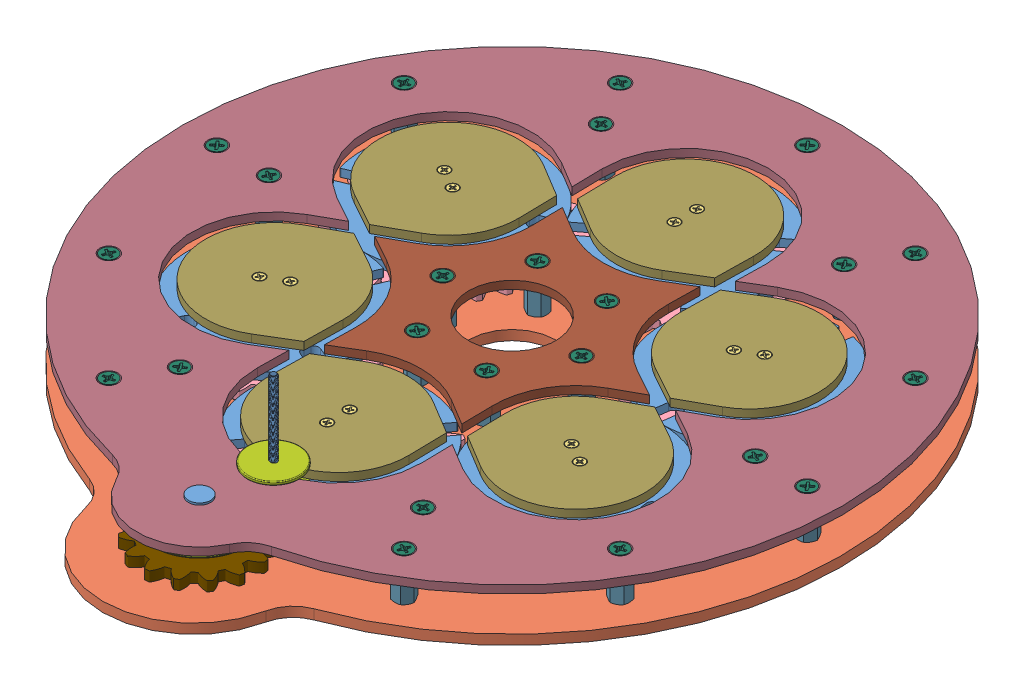
SolidWorks assembly braider_assembly, configuration Default. Lengths in mm.
Overall size (407.81 79.95 544.26).
176 component instances, 26 part files, 54 mates.
Components (placement in the parent):
- Assem3-1: Assem3 [Default] at (8.7677 19.1661 -76.7438) x (-0.794369 0 0.607435) z (-0.607435 0 -0.794369) size (188.23 25.6 124.49)
  - transfer_plate-4: transfer_plate [Default] at (0 -4.5661 0) size (188.23 4.5 124.49)
  - handoff_shaft-1: handoff_shaft [Default] at (0 -4.5661 0) x (-0.685538 0 0.728037) z (-0.728037 0 -0.685538) size (25.4 25.6 25.4)
  - transfer_spacer-1: transfer_spacer [Default] at (0 -9.0661 0) x (0 0 -1) z (0 1 0) size (40 40 4.5)
  - 25 tooth large gear2-2: 25 tooth large gear2 [Default] at (0 -13.5661 0) size (105.94 4.5 105.74)
  - 91771A169-1: 91771A169 [91771A169] at (0 -2.1743 16.8627) x (1 0 0) z (0 1 0) size (6.65 6.65 15.37)
  - 91771A169-2: 91771A169 [91771A169] at (0 -2.1743 -16.8627) x (1 0 0) z (0 1 0) size (6.65 6.65 15.37)
- Assem3-2: Assem3 [Default] at (-77.8348 19.1661 -26.7438) x (0.923102 0 -0.384556) z (0.384556 0 0.923102) size (188.23 25.6 124.49)
  - transfer_plate-4: transfer_plate [Default] at (0 -4.5661 0) size (188.23 4.5 124.49)
  - handoff_shaft-1: handoff_shaft [Default] at (0 -4.5661 0) x (-0.685538 0 0.728037) z (-0.728037 0 -0.685538) size (25.4 25.6 25.4)
  - transfer_spacer-1: transfer_spacer [Default] at (0 -9.0661 0) x (0 0 -1) z (0 1 0) size (40 40 4.5)
  - 25 tooth large gear2-2: 25 tooth large gear2 [Default] at (0 -13.5661 0) size (105.94 4.5 105.74)
  - 91771A169-1: 91771A169 [91771A169] at (0 -2.1743 16.8627) x (1 0 0) z (0 1 0) size (6.65 6.65 15.37)
  - 91771A169-2: 91771A169 [91771A169] at (0 -2.1743 -16.8627) x (1 0 0) z (0 1 0) size (6.65 6.65 15.37)
- Assem3-3: Assem3 [Default] at (-77.8348 19.1661 73.2562) x (0.922465 0 0.386081) z (-0.386081 0 0.922465) size (188.23 25.6 124.49)
  - transfer_plate-4: transfer_plate [Default] at (0 -4.5661 0) size (188.23 4.5 124.49)
  - handoff_shaft-1: handoff_shaft [Default] at (0 -4.5661 0) x (-0.685538 0 0.728037) z (-0.728037 0 -0.685538) size (25.4 25.6 25.4)
  - transfer_spacer-1: transfer_spacer [Default] at (0 -9.0661 0) x (0 0 -1) z (0 1 0) size (40 40 4.5)
  - 25 tooth large gear2-2: 25 tooth large gear2 [Default] at (0 -13.5661 0) size (105.94 4.5 105.74)
  - 91771A169-1: 91771A169 [91771A169] at (0 -2.1743 16.8627) x (1 0 0) z (0 1 0) size (6.65 6.65 15.37)
  - 91771A169-2: 91771A169 [91771A169] at (0 -2.1743 -16.8627) x (1 0 0) z (0 1 0) size (6.65 6.65 15.37)
- Assem3-4: Assem3 [Default] at (8.7677 19.1661 123.2562) x (-0.795809 0 -0.605547) z (0.605547 0 -0.795809) size (188.23 25.6 124.49)
  - transfer_plate-4: transfer_plate [Default] at (0 -4.5661 0) size (188.23 4.5 124.49)
  - handoff_shaft-1: handoff_shaft [Default] at (0 -4.5661 0) x (-0.685538 0 0.728037) z (-0.728037 0 -0.685538) size (25.4 25.6 25.4)
  - transfer_spacer-1: transfer_spacer [Default] at (0 -9.0661 0) x (0 0 -1) z (0 1 0) size (40 40 4.5)
  - 25 tooth large gear2-2: 25 tooth large gear2 [Default] at (0 -13.5661 0) size (105.94 4.5 105.74)
  - 91771A169-1: 91771A169 [91771A169] at (0 -2.1743 16.8627) x (1 0 0) z (0 1 0) size (6.65 6.65 15.37)
  - 91771A169-2: 91771A169 [91771A169] at (0 -2.1743 -16.8627) x (1 0 0) z (0 1 0) size (6.65 6.65 15.37)
- Assem3-5: Assem3 [Default] at (95.3702 19.1661 73.2562) x (-0.130269 0 -0.991479) z (0.991479 0 -0.130269) size (188.23 25.6 124.49)
  - transfer_plate-4: transfer_plate [Default] at (0 -4.5661 0) size (188.23 4.5 124.49)
  - handoff_shaft-1: handoff_shaft [Default] at (0 -4.5661 0) x (-0.685538 0 0.728037) z (-0.728037 0 -0.685538) size (25.4 25.6 25.4)
  - transfer_spacer-1: transfer_spacer [Default] at (0 -9.0661 0) x (0 0 -1) z (0 1 0) size (40 40 4.5)
  - 25 tooth large gear2-2: 25 tooth large gear2 [Default] at (0 -13.5661 0) size (105.94 4.5 105.74)
  - 91771A169-1: 91771A169 [91771A169] at (0 -2.1743 16.8627) x (1 0 0) z (0 1 0) size (6.65 6.65 15.37)
  - 91771A169-2: 91771A169 [91771A169] at (0 -2.1743 -16.8627) x (1 0 0) z (0 1 0) size (6.65 6.65 15.37)
- Assem3-6: Assem3 [Default] at (95.3702 19.1661 -26.7438) x (-0.130469 0 0.991452) z (-0.991452 0 -0.130469) size (188.23 25.6 124.49)
  - transfer_plate-4: transfer_plate [Default] at (0 -4.5661 0) size (188.23 4.5 124.49)
  - handoff_shaft-1: handoff_shaft [Default] at (0 -4.5661 0) x (-0.685538 0 0.728037) z (-0.728037 0 -0.685538) size (25.4 25.6 25.4)
  - transfer_spacer-1: transfer_spacer [Default] at (0 -9.0661 0) x (0 0 -1) z (0 1 0) size (40 40 4.5)
  - 25 tooth large gear2-2: 25 tooth large gear2 [Default] at (0 -13.5661 0) size (105.94 4.5 105.74)
  - 91771A169-1: 91771A169 [91771A169] at (0 -2.1743 16.8627) x (1 0 0) z (0 1 0) size (6.65 6.65 15.37)
  - 91771A169-2: 91771A169 [91771A169] at (0 -2.1743 -16.8627) x (1 0 0) z (0 1 0) size (6.65 6.65 15.37)
- Part11-1: Part11 [Default] x (1 0 0) z (0 1 0) size (200 378.38 5.6)
- Part15-1: Part15 [Default] at (-86.6025 0 -50) x (-0.916904 0 0.399107) z (0 1 0)
- spindle_sub_assembly-5: spindle_sub_assembly [Default] at (38.2222 14.0833 186.1922) x (0.387319 0 -0.921946) z (-0.921946 0 -0.387319) size (37.67 65.55 37.67)
  - spindle_shaft-1: spindle_shaft [Default] at (9.1523 -6.9167 29.8135) size (8 5.6 8)
  - top_ring-1: top_ring [Default] at (4.3402 31.9804 168.7359) x (0.991452 0.000169 -0.130469) z (0.000177 -1 0.000051) size (30 30 2.01)
  - top_ring-2: top_ring [Default] at (-10.4741 23.8804 -107.7998) x (-0.953205 0.000169 0.302326) z (-0.000183 -1 -0.000019) size (30 30 2.01)
  - oval_slider-1: oval_slider [Default] at (9.1523 -10.4167 29.8135) x (0.496424 0 -0.86808) z (-0.86808 0 -0.496424) size (21.5 5.6 6.52)
  - 4_8_shim-4: 4_8_shim [Default] at (9.1523 -10.4167 29.8135) size (8 0.5 8)
  - 4_8_shim-5: 4_8_shim [Default] at (9.1523 -7.9167 29.8135) size (8 0.5 8)
  - 4_8_shim-6: 4_8_shim [Default] at (9.1523 -7.4167 29.8135) size (8 0.5 8)
  - m4_60mm-1: m4_60mm [92000A248] at (9.1523 -61.3167 29.8135) x (1 0 0) z (0 1 0) size (8 8 65.55)
- top_slide_plate_sub_assembly-1: top_slide_plate_sub_assembly [Default] at (8.7677 30.1 23.2562) x (-1 0 0) z (0 0 -1) size (407.81 4.5 419.9)
  - top_slide_plate_inner_ring-1: top_slide_plate_inner_ring [Default] at (0 -67.0456 0) x (-1 0 0) z (0 1 0) size (198.46 137.03 4.5)
  - top_slide_plate_segment-1: top_slide_plate_segment [Default] at (-1.731 0 -94.8037) x (1 0 0) z (0 0 -1) size (111.69 4.5 164.88)
  - top_slide_plate_segment-13: top_slide_plate_segment [Default] at (81.2369 0 -48.9009) x (0.5 0 0.866025) z (0.866025 0 -0.5) size (111.69 4.5 164.88)
  - top_slide_plate_segment-14: top_slide_plate_segment [Default] at (82.9679 0 45.9028) x (-0.5 0 0.866025) z (0.866025 0 0.5) size (111.69 4.5 164.88)
  - top_slide_plate_segment-15: top_slide_plate_segment [Default] at (1.731 0 94.8037) x (-1 0 0) z (0 0 1) size (111.69 4.5 164.88)
  - top_slide_plate_segment-16: top_slide_plate_segment [Default] at (-81.2369 0 48.9009) x (-0.5 0 -0.866025) z (-0.866025 0 0.5) size (111.69 4.5 164.88)
  - top_slide_plate_segment-17: top_slide_plate_segment [Default] at (-82.9679 0 -45.9028) x (0.5 0 -0.866025) z (-0.866025 0 -0.5) size (111.69 4.5 164.88)
  - top_slide_plate_outer_ring-2: top_slide_plate_outer_ring [Default] at origin size (407.81 4.5 419.9)
- standoff-7: standoff [95947A731] at (-76.2323 15.6 170.4805) x (-0.868924 0 0.494945) z (0 -1 0) size (10 11.55 21.1)
- m5 14mm-1: m5 14mm [91420A324] at (-61.2323 27.6 144.4998) x (0.552479 0 0.833527) z (0 1 0) size (9.2 9.2 14.67)
- m5 14mm-13: m5 14mm [91420A324] at (-76.2323 27.6 170.4805) x (-0.986594 0 0.163192) z (0 1 0) size (9.2 9.2 14.67)
- m5 14mm-19: m5 14mm [91420A324] at (-11.2323 27.6 -11.3848) x (-0.401704 0 -0.915769) z (0 1 0) size (9.2 9.2 14.67)
- slider_bearing_assembly-1: slider_bearing_assembly [Default] at (-0.8143 7.35 212.7934) x (1 0 0) z (0 -1 0) size (10 10 3.75)
  - 6-32_thead__175_thick-1-1: 6-32_thead__175_thick-1 [Default] at (-3.85 0 -1.125) size (1.08 1.08 1.75)
    - 6-32_thead__125_thick-1-1: 6-32_thead__125_thick-1 [Default] at (0 0 0.2386) size (1.08 1.08 1.27)
    - 6-32_thead__175_thick-1-1: 6-32_thead__175_thick-1 [Default] at origin size (1.08 1.08 0.48)
  - 6-32_thead__175_thick-1-2: 6-32_thead__175_thick-1 [Default] at (-2.7224 2.7224 -1.125) x (0.707107 -0.707107 0) z (0 0 1) size (1.08 1.08 1.75)
    - 6-32_thead__125_thick-1-1: 6-32_thead__125_thick-1 [Default] at (0 0 0.2386) size (1.08 1.08 1.27)
    - 6-32_thead__175_thick-1-1: 6-32_thead__175_thick-1 [Default] at origin size (1.08 1.08 0.48)
  - 6-32_thead__175_thick-1-3: 6-32_thead__175_thick-1 [Default] at (0 3.85 -1.125) x (0 -1 0) z (0 0 1) size (1.08 1.08 1.75)
    - 6-32_thead__125_thick-1-1: 6-32_thead__125_thick-1 [Default] at (0 0 0.2386) size (1.08 1.08 1.27)
    - 6-32_thead__175_thick-1-1: 6-32_thead__175_thick-1 [Default] at origin size (1.08 1.08 0.48)
  - 6-32_thead__175_thick-1-4: 6-32_thead__175_thick-1 [Default] at (2.7224 2.7224 -1.125) x (-0.707107 -0.707107 0) z (0 0 1) size (1.08 1.08 1.75)
    - 6-32_thead__125_thick-1-1: 6-32_thead__125_thick-1 [Default] at (0 0 0.2386) size (1.08 1.08 1.27)
    - 6-32_thead__175_thick-1-1: 6-32_thead__175_thick-1 [Default] at origin size (1.08 1.08 0.48)
  - 6-32_thead__175_thick-1-5: 6-32_thead__175_thick-1 [Default] at (3.85 0 -1.125) x (-1 0 0) z (0 0 1) size (1.08 1.08 1.75)
    - 6-32_thead__125_thick-1-1: 6-32_thead__125_thick-1 [Default] at (0 0 0.2386) size (1.08 1.08 1.27)
    - 6-32_thead__175_thick-1-1: 6-32_thead__175_thick-1 [Default] at origin size (1.08 1.08 0.48)
  - 6-32_thead__175_thick-1-6: 6-32_thead__175_thick-1 [Default] at (2.7224 -2.7224 -1.125) x (-0.707107 0.707107 0) z (0 0 1) size (1.08 1.08 1.75)
    - 6-32_thead__125_thick-1-1: 6-32_thead__125_thick-1 [Default] at (0 0 0.2386) size (1.08 1.08 1.27)
    - 6-32_thead__175_thick-1-1: 6-32_thead__175_thick-1 [Default] at origin size (1.08 1.08 0.48)
  - 6-32_thead__175_thick-1-7: 6-32_thead__175_thick-1 [Default] at (0 -3.85 -1.125) x (0 1 0) z (0 0 1) size (1.08 1.08 1.75)
    - 6-32_thead__125_thick-1-1: 6-32_thead__125_thick-1 [Default] at (0 0 0.2386) size (1.08 1.08 1.27)
    - 6-32_thead__175_thick-1-1: 6-32_thead__175_thick-1 [Default] at origin size (1.08 1.08 0.48)
  - 6-32_thead__175_thick-1-8: 6-32_thead__175_thick-1 [Default] at (-2.7224 -2.7224 -1.125) x (0.707107 0.707107 0) z (0 0 1) size (1.08 1.08 1.75)
    - 6-32_thead__125_thick-1-1: 6-32_thead__125_thick-1 [Default] at (0 0 0.2386) size (1.08 1.08 1.27)
    - 6-32_thead__175_thick-1-1: 6-32_thead__175_thick-1 [Default] at origin size (1.08 1.08 0.48)
  - 6-32_thead__175_thick-1-9: 6-32_thead__175_thick-1 [Default] at (0 3.85 0.875) x (0.707107 -0.707107 0) z (0 0 1) size (1.08 1.08 1.75)
    - 6-32_thead__125_thick-1-1: 6-32_thead__125_thick-1 [Default] at (0 0 0.2386) size (1.08 1.08 1.27)
    - 6-32_thead__175_thick-1-1: 6-32_thead__175_thick-1 [Default] at origin size (1.08 1.08 0.48)
  - 6-32_thead__175_thick-1-10: 6-32_thead__175_thick-1 [Default] at (-2.7224 2.7224 0.875) size (1.08 1.08 1.75)
    - 6-32_thead__125_thick-1-1: 6-32_thead__125_thick-1 [Default] at (0 0 0.2386) size (1.08 1.08 1.27)
    - 6-32_thead__175_thick-1-1: 6-32_thead__175_thick-1 [Default] at origin size (1.08 1.08 0.48)
  - 6-32_thead__175_thick-1-11: 6-32_thead__175_thick-1 [Default] at (-3.85 0 0.875) x (0.707107 0.707107 0) z (0 0 1) size (1.08 1.08 1.75)
    - 6-32_thead__125_thick-1-1: 6-32_thead__125_thick-1 [Default] at (0 0 0.2386) size (1.08 1.08 1.27)
    - 6-32_thead__175_thick-1-1: 6-32_thead__175_thick-1 [Default] at origin size (1.08 1.08 0.48)
  - 6-32_thead__175_thick-1-12: 6-32_thead__175_thick-1 [Default] at (-2.7224 -2.7224 0.875) x (0 1 0) z (0 0 1) size (1.08 1.08 1.75)
    - 6-32_thead__125_thick-1-1: 6-32_thead__125_thick-1 [Default] at (0 0 0.2386) size (1.08 1.08 1.27)
    - 6-32_thead__175_thick-1-1: 6-32_thead__175_thick-1 [Default] at origin size (1.08 1.08 0.48)
  - 6-32_thead__175_thick-1-13: 6-32_thead__175_thick-1 [Default] at (0 -3.85 0.875) x (-0.707107 0.707107 0) z (0 0 1) size (1.08 1.08 1.75)
    - 6-32_thead__125_thick-1-1: 6-32_thead__125_thick-1 [Default] at (0 0 0.2386) size (1.08 1.08 1.27)
    - 6-32_thead__175_thick-1-1: 6-32_thead__175_thick-1 [Default] at origin size (1.08 1.08 0.48)
  - 6-32_thead__175_thick-1-14: 6-32_thead__175_thick-1 [Default] at (2.7224 -2.7224 0.875) x (-1 0 0) z (0 0 1) size (1.08 1.08 1.75)
    - 6-32_thead__125_thick-1-1: 6-32_thead__125_thick-1 [Default] at (0 0 0.2386) size (1.08 1.08 1.27)
    - 6-32_thead__175_thick-1-1: 6-32_thead__175_thick-1 [Default] at origin size (1.08 1.08 0.48)
  - 6-32_thead__175_thick-1-15: 6-32_thead__175_thick-1 [Default] at (3.85 0 0.875) x (-0.707107 -0.707107 0) z (0 0 1) size (1.08 1.08 1.75)
    - 6-32_thead__125_thick-1-1: 6-32_thead__125_thick-1 [Default] at (0 0 0.2386) size (1.08 1.08 1.27)
    - 6-32_thead__175_thick-1-1: 6-32_thead__175_thick-1 [Default] at origin size (1.08 1.08 0.48)
  - 6-32_thead__175_thick-1-16: 6-32_thead__175_thick-1 [Default] at (2.7224 2.7224 0.875) x (0 -1 0) z (0 0 1) size (1.08 1.08 1.75)
    - 6-32_thead__125_thick-1-1: 6-32_thead__125_thick-1 [Default] at (0 0 0.2386) size (1.08 1.08 1.27)
    - 6-32_thead__175_thick-1-1: 6-32_thead__175_thick-1 [Default] at origin size (1.08 1.08 0.48)
  - 545364-1-1: 545364-1 [Default] at origin size (10 10 3.75)
- standoff-35: standoff [95947A731] at (-11.2323 15.6 -11.3848) x (1 0 0) z (0 -1 0) size (10 11.55 21.1)
- standoff-41: standoff [95947A731] at (-61.2323 15.6 144.4998) x (1 0 0) z (0 -1 0) size (10 11.55 21.1)
- 2 inch pulley-2: 2 inch pulley [Default] at (8.7774 21.233 203.2562) x (-0.976231 0 -0.216734) z (0 -1 0) size (53.81 53.81 6.1)
- half inch bore hub mount-2: half inch bore hub mount [Default] at (8.7774 8.66 203.2562) x (-0.976231 0 -0.216734) z (0.216734 0 -0.976231) size (20.57 6.99 20.57)
- 15 tooth small gear-4: 15 tooth small gear [Default] at (8.7774 5.6 203.2562) x (-0.999686 0 -0.025054) z (0.025054 0 -0.999686) size (65.52 5.6 65.88)
- half inch shaft-1: half inch shaft [Default] at (8.7774 18.9636 203.2562) x (-0.9981 0 -0.061613) z (0.061613 0 -0.9981) size (12.7 31.2 12.7)
- Part13-2: Part13 [Default] at (8.7677 5.6 23.2562) x (-1 0 0) z (0 0 -1) size (380 5.6 527.68)
- standoff-42: standoff [95947A731] at (-138.4566 15.6 108.2562) x (-0.999983 0 -0.005827) z (0 -1 0) size (10 11.55 21.1)
- standoff-43: standoff [95947A731] at (-161.2323 15.6 23.2562) x (-0.863097 0 -0.505038) z (0 -1 0) size (10 11.55 21.1)
- standoff-44: standoff [95947A731] at (-138.4566 15.6 -61.7438) x (-0.494945 0 -0.868924) z (0 -1 0) size (10 11.55 21.1)
- standoff-45: standoff [95947A731] at (-76.2323 15.6 -123.9681) x (0.005827 0 -0.999983) z (0 -1 0) size (10 11.55 21.1)
- standoff-46: standoff [95947A731] at (8.7677 15.6 -146.7438) x (0.505038 0 -0.863097) z (0 -1 0) size (10 11.55 21.1)
- standoff-47: standoff [95947A731] at (93.7677 15.6 -123.9681) x (0.868924 0 -0.494945) z (0 -1 0) size (10 11.55 21.1)
- standoff-48: standoff [95947A731] at (155.992 15.6 -61.7438) x (0.999983 0 0.005827) z (0 -1 0) size (10 11.55 21.1)
- standoff-49: standoff [95947A731] at (178.7677 15.6 23.2562) x (0.863097 0 0.505038) z (0 -1 0) size (10 11.55 21.1)
- standoff-50: standoff [95947A731] at (155.992 15.6 108.2562) x (0.494945 0 0.868924) z (0 -1 0) size (10 11.55 21.1)
- standoff-51: standoff [95947A731] at (93.7677 15.6 170.4805) x (-0.005827 0 0.999983) z (0 -1 0) size (10 11.55 21.1)
- standoff-52: standoff [95947A731] at (-131.2323 15.6 23.2562) x (0.5 0 0.866025) z (0 -1 0) size (10 11.55 21.1)
- standoff-53: standoff [95947A731] at (-61.2323 15.6 -97.9873) x (-0.5 0 0.866025) z (0 -1 0) size (10 11.55 21.1)
- standoff-54: standoff [95947A731] at (78.7677 15.6 -97.9873) x (-1 0 0) z (0 -1 0) size (10 11.55 21.1)
- standoff-55: standoff [95947A731] at (148.7677 15.6 23.2562) x (-0.5 0 -0.866025) z (0 -1 0) size (10 11.55 21.1)
- standoff-56: standoff [95947A731] at (78.7677 15.6 144.4998) x (0.5 0 -0.866025) z (0 -1 0) size (10 11.55 21.1)
- standoff-57: standoff [95947A731] at (-31.2323 15.6 23.2562) x (0.5 0 -0.866025) z (0 -1 0) size (10 11.55 21.1)
- standoff-58: standoff [95947A731] at (-11.2323 15.6 57.8972) x (-0.5 0 -0.866025) z (0 -1 0) size (10 11.55 21.1)
- standoff-59: standoff [95947A731] at (28.7677 15.6 57.8972) x (-1 0 0) z (0 -1 0) size (10 11.55 21.1)
- standoff-60: standoff [95947A731] at (48.7677 15.6 23.2562) x (-0.5 0 0.866025) z (0 -1 0) size (10 11.55 21.1)
- standoff-61: standoff [95947A731] at (28.7677 15.6 -11.3848) x (0.5 0 0.866025) z (0 -1 0) size (10 11.55 21.1)
- m5 14mm-20: m5 14mm [91420A324] at (-138.4566 27.6 108.2562) x (-0.936012 0 -0.351968) z (0 1 0) size (9.2 9.2 14.67)
- m5 14mm-21: m5 14mm [91420A324] at (-161.2323 27.6 23.2562) x (-0.634626 0 -0.772819) z (0 1 0) size (9.2 9.2 14.67)
- m5 14mm-22: m5 14mm [91420A324] at (-138.4566 27.6 -61.7438) x (-0.163192 0 -0.986594) z (0 1 0) size (9.2 9.2 14.67)
- m5 14mm-23: m5 14mm [91420A324] at (-76.2323 27.6 -123.9681) x (0.351968 0 -0.936012) z (0 1 0) size (9.2 9.2 14.67)
- m5 14mm-24: m5 14mm [91420A324] at (8.7677 27.6 -146.7438) x (0.772819 0 -0.634626) z (0 1 0) size (9.2 9.2 14.67)
- m5 14mm-25: m5 14mm [91420A324] at (93.7677 27.6 -123.9681) x (0.986594 0 -0.163192) z (0 1 0) size (9.2 9.2 14.67)
- m5 14mm-26: m5 14mm [91420A324] at (155.992 27.6 -61.7438) x (0.936012 0 0.351968) z (0 1 0) size (9.2 9.2 14.67)
- m5 14mm-27: m5 14mm [91420A324] at (178.7677 27.6 23.2562) x (0.634626 0 0.772819) z (0 1 0) size (9.2 9.2 14.67)
- m5 14mm-28: m5 14mm [91420A324] at (155.992 27.6 108.2562) x (0.163192 0 0.986594) z (0 1 0) size (9.2 9.2 14.67)
- m5 14mm-29: m5 14mm [91420A324] at (93.7677 27.6 170.4805) x (-0.351968 0 0.936012) z (0 1 0) size (9.2 9.2 14.67)
- m5 14mm-30: m5 14mm [91420A324] at (-131.2323 27.6 23.2562) x (-0.445616 0 0.895224) z (0 1 0) size (9.2 9.2 14.67)
- m5 14mm-31: m5 14mm [91420A324] at (-61.2323 27.6 -97.9873) x (-0.998095 0 0.061697) z (0 1 0) size (9.2 9.2 14.67)
- m5 14mm-32: m5 14mm [91420A324] at (78.7677 27.6 -97.9873) x (-0.552479 0 -0.833527) z (0 1 0) size (9.2 9.2 14.67)
- m5 14mm-33: m5 14mm [91420A324] at (148.7677 27.6 23.2562) x (0.445616 0 -0.895224) z (0 1 0) size (9.2 9.2 14.67)
- m5 14mm-34: m5 14mm [91420A324] at (78.7677 27.6 144.4998) x (0.998095 0 -0.061697) z (0 1 0) size (9.2 9.2 14.67)
- m5 14mm-35: m5 14mm [91420A324] at (-31.2323 27.6 23.2562) x (-0.993932 0 -0.109999) z (0 1 0) size (9.2 9.2 14.67)
- m5 14mm-36: m5 14mm [91420A324] at (-11.2323 27.6 57.8972) x (-0.592228 0 0.805771) z (0 1 0) size (9.2 9.2 14.67)
- m5 14mm-37: m5 14mm [91420A324] at (28.7677 27.6 57.8972) x (0.401704 0 0.915769) z (0 1 0) size (9.2 9.2 14.67)
- m5 14mm-38: m5 14mm [91420A324] at (48.7677 27.6 23.2562) x (0.993932 0 0.109999) z (0 1 0) size (9.2 9.2 14.67)
- m5 14mm-39: m5 14mm [91420A324] at (28.7677 27.6 -11.3848) x (0.592228 0 -0.805771) z (0 1 0) size (9.2 9.2 14.67)
- 3m 20mm long screw-1: 3m 20mm long screw [91420A128] at (-83.464 28.45 76.5062) x (-0.837169 0 -0.546944) z (0 1 0) size (5.6 5.6 21.48)
- 3m 20mm long screw-2: 3m 20mm long screw [91420A128] at (-72.2057 28.45 70.0062) x (-0.837169 0 -0.546944) z (0 1 0) size (5.6 5.6 21.48)
- 3m 20mm long screw-3: 3m 20mm long screw [91420A128] at (-83.464 28.45 -29.9938) x (0.055083 0 -0.998482) z (0 1 0) size (5.6 5.6 21.48)
- 3m 20mm long screw-4: 3m 20mm long screw [91420A128] at (8.7677 28.45 -83.2438) x (0.892252 0 -0.451538) z (0 1 0) size (5.6 5.6 21.48)
- 3m 20mm long screw-5: 3m 20mm long screw [91420A128] at (100.9994 28.45 -29.9938) x (0.837169 0 0.546944) z (0 1 0) size (5.6 5.6 21.48)
- 3m 20mm long screw-6: 3m 20mm long screw [91420A128] at (100.9994 28.45 76.5062) x (-0.055083 0 0.998482) z (0 1 0) size (5.6 5.6 21.48)
- 3m 20mm long screw-7: 3m 20mm long screw [91420A128] at (8.7677 28.45 129.7562) x (-0.892252 0 0.451538) z (0 1 0) size (5.6 5.6 21.48)
- 3m 20mm long screw-8: 3m 20mm long screw [91420A128] at (-72.2057 28.45 -23.4938) x (0.055083 0 -0.998482) z (0 1 0) size (5.6 5.6 21.48)
- 3m 20mm long screw-9: 3m 20mm long screw [91420A128] at (8.7677 28.45 -70.2438) x (0.892252 0 -0.451538) z (0 1 0) size (5.6 5.6 21.48)
- 3m 20mm long screw-10: 3m 20mm long screw [91420A128] at (89.7411 28.45 -23.4938) x (0.837169 0 0.546944) z (0 1 0) size (5.6 5.6 21.48)
- 3m 20mm long screw-11: 3m 20mm long screw [91420A128] at (89.7411 28.45 70.0062) x (-0.055083 0 0.998482) z (0 1 0) size (5.6 5.6 21.48)
- 3m 20mm long screw-12: 3m 20mm long screw [91420A128] at (8.7677 28.45 116.7562) x (-0.892252 0 0.451538) z (0 1 0) size (5.6 5.6 21.48)
- m5 14mm-40: m5 14mm [91420A324] at (-76.2323 2.5 170.4805) x (-0.837169 0 -0.546944) z (0 -1 0) size (9.2 9.2 14.67)
Mates (geometry in assembly coordinates):
- Concentric125: concentric anti-aligned: circle of top_slide_plate_sub_assembly-1/top_slide_plate_inner_ring-1; circle of m5 14mm-19
- GearMate1: gear = 25.4 : 25.4 mm: cylinder of ? through (-86.6025 11.2 50) axis (0 -1 0) radius 12.7; cylinder of ? through (0 11.2 100) axis (0 -1 0) radius 12.7
- GearMate2: gear = 25.4 : 25.4 mm: cylinder of ? through (-86.6025 11.2 50) axis (0 -1 0) radius 12.7; cylinder of ? through (-86.6025 11.2 -50) axis (0 -1 0) radius 12.7
- GearMate3: gear = 25.4 : 25.4 mm: cylinder of ? through (-86.6025 11.2 -50) axis (0 -1 0) radius 12.7; cylinder of ? through (0 11.2 -100) axis (0 -1 0) radius 12.7
- GearMate4: gear = 25.4 : 25.4 mm: cylinder of ? through (0 11.2 -100) axis (0 -1 0) radius 12.7; cylinder of ? through (86.6025 11.2 -50) axis (0 -1 0) radius 12.7
- GearMate5: gear = 25.4 : 25.4 mm: cylinder of ? through (86.6025 11.2 -50) axis (0 -1 0) radius 12.7; cylinder of ? through (86.6025 11.2 50) axis (0 -1 0) radius 12.7
- GearMate6: gear = 25.4 : 25.4 mm: cylinder of Assem3-1/25 tooth large gear2-2 through (8.7677 10.1 -76.7438) axis (0 -1 0) radius 12.7; cylinder of Assem3-6/25 tooth large gear2-2 through (95.3702 10.1 -26.7438) axis (0 -1 0) radius 12.7
- GearMate7: gear = 25.4 : 25.4 mm: cylinder of Assem3-5/25 tooth large gear2-2 through (95.3702 10.1 73.2562) axis (0 -1 0) radius 12.7; cylinder of Assem3-4/25 tooth large gear2-2 through (8.7677 10.1 123.2562) axis (0 -1 0) radius 12.7
- GearMate8: gear = 25.4 : 25.4 mm: cylinder of Assem3-4/25 tooth large gear2-2 through (8.7677 10.1 123.2562) axis (0 -1 0) radius 12.7; cylinder of Assem3-3/25 tooth large gear2-2 through (-77.8348 10.1 73.2562) axis (0 -1 0) radius 12.7
- GearMate9: gear = 25.4 : 25.4 mm: cylinder of Assem3-3/25 tooth large gear2-2 through (-77.8348 10.1 73.2562) axis (0 -1 0) radius 12.7; cylinder of Assem3-2/25 tooth large gear2-2 through (-77.8348 10.1 -26.7438) axis (0 -1 0) radius 12.7
- GearMate10: gear = 25.4 : 25.4 mm: cylinder of Assem3-2/25 tooth large gear2-2 through (-77.8348 10.1 -26.7438) axis (0 -1 0) radius 12.7; cylinder of Assem3-1/25 tooth large gear2-2 through (8.7677 10.1 -76.7438) axis (0 -1 0) radius 12.7
- Concentric133: concentric aligned: cylinder of 2 inch pulley-2 through (8.7774 24.281 203.2562) axis (0 1 0) radius 6.3627; cylinder of half inch bore hub mount-2 through (8.7774 18.185 203.2562) axis (0 1 0) radius 6.35
- Coincident210: coincident anti-aligned: plane of 2 inch pulley-2 through (-17.488 18.185 197.425) normal (0 -1 0); plane of half inch bore hub mount-2 through (11.4033 18.185 207.3808) normal (0 1 0)
- Concentric144: concentric aligned: cylinder of 15 tooth small gear-4 through (8.7774 11.2 203.2562) axis (0 -1 0) radius 6.35; cylinder of half inch shaft-1 through (8.7774 49.1605 203.2562) axis (0 -1 0) radius 6.35
- Coincident226: coincident anti-aligned: plane of half inch bore hub mount-2 through (11.4033 11.2 207.3808) normal (0 -1 0); plane of 15 tooth small gear-4 through (8.7774 11.2 203.2562) normal (0 1 0)
- Concentric145: concentric anti-aligned: cylinder of 2 inch pulley-2 through (8.7774 24.281 203.2562) axis (0 1 0) radius 6.3627; cylinder of half inch shaft-1 through (8.7774 49.1605 203.2562) axis (0 -1 0) radius 6.35
- Coincident231: coincident: plane of Part13-2 through (44.475 0 121.9983) normal (0 -1 0); plane of assembly through (0 0 0) normal (0 1 0)
- Concentric148: concentric anti-aligned: cylinder of top_slide_plate_sub_assembly-1/top_slide_plate_inner_ring-1 through (8.7677 30.1 23.2562) axis (0 -1 0) radius 25; cylinder of Part13-2 through (8.7677 0 23.2562) axis (0 1 0) radius 25
- Coincident233: coincident aligned: plane of top_slide_plate_sub_assembly-1/top_slide_plate_outer_ring-2 through (34.1205 30.1 125.1495) normal (0 1 0); plane of m5 14mm-1 through (-61.2323 30.1 144.4998) normal (0 1 0)
- Concentric149: concentric anti-aligned: cylinder of top_slide_plate_sub_assembly-1/top_slide_plate_outer_ring-2 through (-61.2323 30.1 144.4998) axis (0 1 0) radius 2.75; circle of m5 14mm-1
- Coincident234: coincident aligned: plane of top_slide_plate_sub_assembly-1/top_slide_plate_outer_ring-2 through (34.1205 30.1 125.1495) normal (0 1 0); plane of m5 14mm-19 through (-11.2323 30.1 -11.3848) normal (0 1 0)
- Coincident235: coincident aligned: plane of top_slide_plate_sub_assembly-1/top_slide_plate_outer_ring-2 through (34.1205 30.1 125.1495) normal (0 1 0); plane of m5 14mm-13 through (-76.2323 30.1 170.4805) normal (0 1 0)
- Concentric150: concentric anti-aligned: cylinder of top_slide_plate_sub_assembly-1/top_slide_plate_outer_ring-2 through (-76.2323 30.1 170.4805) axis (0 1 0) radius 2.75; circle of m5 14mm-13
- Coincident236: coincident anti-aligned: plane of top_slide_plate_sub_assembly-1/top_slide_plate_outer_ring-2 through (34.1205 25.6 125.1495) normal (0 -1 0); plane of standoff-7 through (-79.0899 25.6 165.4638) normal (0 1 0)
- Concentric151: concentric aligned: cylinder of top_slide_plate_sub_assembly-1/top_slide_plate_outer_ring-2 through (-76.2323 30.1 170.4805) axis (0 1 0) radius 2.75; circle of standoff-7
- Coincident237: coincident anti-aligned: plane of top_slide_plate_sub_assembly-1/top_slide_plate_inner_ring-1 through (8.7677 25.6 23.2562) normal (0 -1 0); plane of standoff-35 through (-11.2323 25.6 -5.6113) normal (0 1 0)
- Concentric152: concentric aligned: cylinder of top_slide_plate_sub_assembly-1/top_slide_plate_inner_ring-1 through (-11.2323 30.1 -11.3848) axis (0 1 0) radius 2.75; circle of standoff-35
- Coincident238: coincident anti-aligned: plane of top_slide_plate_sub_assembly-1/top_slide_plate_outer_ring-2 through (34.1205 25.6 125.1495) normal (0 -1 0); plane of standoff-41 through (-61.2323 25.6 150.2733) normal (0 1 0)
- Concentric153: concentric aligned: cylinder of top_slide_plate_sub_assembly-1/top_slide_plate_outer_ring-2 through (-61.2323 30.1 144.4998) axis (0 1 0) radius 2.75; circle of standoff-41
- Coincident239: coincident anti-aligned: plane of Assem3-1/25 tooth large gear2-2 through (35.2101 5.6 -35.932) normal (0 -1 0); plane of Part13-2 through (44.475 5.6 121.9983) normal (0 1 0)
- Concentric154: concentric anti-aligned: cylinder of Assem3-1/handoff_shaft-1 through (8.7677 59.321 -76.7438) axis (0 -1 0) radius 12.7; cylinder of Part13-2 through (8.7677 0 -76.7438) axis (0 1 0) radius 12.7
- Concentric155: concentric anti-aligned: cylinder of Assem3-3/handoff_shaft-1 through (-77.8348 59.321 73.2562) axis (0 -1 0) radius 12.7; cylinder of Part13-2 through (-77.8348 -14.4 73.2562) axis (0 1 0) radius 12.7
- Coincident240: coincident anti-aligned: plane of Assem3-3/25 tooth large gear2-2 through (-55.625 5.6 29.9951) normal (0 -1 0); plane of Part13-2 through (44.475 5.6 121.9983) normal (0 1 0)
- Concentric156: concentric anti-aligned: cylinder of Assem3-4/handoff_shaft-1 through (8.7677 59.321 123.2562) axis (0 -1 0) radius 12.7; cylinder of Part13-2 through (8.7677 -14.4 123.2562) axis (0 1 0) radius 12.7
- Coincident241: coincident anti-aligned: plane of Assem3-4/25 tooth large gear2-2 through (-23.6027 5.6 159.5461) normal (0 -1 0); plane of Part13-2 through (44.475 5.6 121.9983) normal (0 1 0)
- Concentric157: concentric anti-aligned: cylinder of Assem3-2/handoff_shaft-1 through (-77.8348 59.321 -26.7438) axis (0 -1 0) radius 12.7; cylinder of Part13-2 through (-77.8348 -14.4 -26.7438) axis (0 1 0) radius 12.7
- Coincident242: coincident anti-aligned: plane of Assem3-2/25 tooth large gear2-2 through (-92.9844 5.6 -72.953) normal (0 -1 0); plane of Part13-2 through (44.475 5.6 121.9983) normal (0 1 0)
- Concentric158: concentric anti-aligned: cylinder of Assem3-5/handoff_shaft-1 through (95.3702 59.321 73.2562) axis (0 -1 0) radius 12.7; cylinder of Part13-2 through (95.3702 -14.4 73.2562) axis (0 1 0) radius 12.7
- Coincident243: coincident anti-aligned: plane of Assem3-5/25 tooth large gear2-2 through (46.8086 5.6 75.8187) normal (0 -1 0); plane of Part13-2 through (44.475 5.6 121.9983) normal (0 1 0)
- Concentric159: concentric anti-aligned: cylinder of Assem3-6/handoff_shaft-1 through (95.3702 59.321 -26.7438) axis (0 -1 0) radius 12.7; cylinder of Part13-2 through (95.3702 -14.4 -26.7438) axis (0 1 0) radius 12.7
- Coincident244: coincident anti-aligned: plane of Assem3-6/25 tooth large gear2-2 through (142.9436 5.6 -16.6653) normal (0 -1 0); plane of Part13-2 through (44.475 5.6 121.9983) normal (0 1 0)
- Coincident249: coincident anti-aligned: plane of standoff-7 through (-79.0899 5.6 165.4638) normal (0 -1 0); plane of Part13-2 through (44.475 5.6 121.9983) normal (0 1 0)
- Coincident250: coincident anti-aligned: plane of spindle_sub_assembly-5/top_ring-2 through (14.2806 30.1 166.2069) normal (0 -1 0); plane of top_slide_plate_sub_assembly-1/top_slide_plate_outer_ring-2 through (34.1205 30.1 125.1495) normal (0 1 0)
- Concentric160: concentric aligned: circle of standoff-7; cylinder of Part13-2 through (-76.2323 5.6 170.4805) axis (0 1 0) radius 2.5
- Coincident252: coincident anti-aligned: plane of 15 tooth small gear-4 through (8.7774 5.6 203.2562) normal (0 -1 0); plane of Part13-2 through (44.475 5.6 121.9983) normal (0 1 0)
- Concentric162: concentric aligned: cylinder of half inch shaft-1 through (8.7774 49.1605 203.2562) axis (0 1 0) radius 6.35; cylinder of Part13-2 through (8.7774 0 203.2562) axis (0 1 0) radius 6.35
- GearMate11: gear = 12.7 : 25.4 mm: cylinder of Assem3-4/25 tooth large gear2-2 through (8.7677 10.1 123.2562) axis (0 -1 0) radius 12.7; cylinder of 15 tooth small gear-4 through (8.7774 11.2 203.2562) axis (0 -1 0) radius 6.35
- Coincident255: coincident anti-aligned: plane of top_slide_plate_sub_assembly-1/top_slide_plate_segment-14 through (-77.8348 25.6 -26.7438) normal (0 -1 0); circle of ?
- Coincident256: coincident aligned: plane of top_slide_plate_sub_assembly-1/top_slide_plate_segment-13 through (-77.8348 30.1 73.2562) normal (0 1 0); plane of 3m 20mm long screw-1 through (-83.464 30.1 76.5062) normal (0 1 0)
- Concentric163: concentric anti-aligned: cylinder of top_slide_plate_sub_assembly-1/top_slide_plate_segment-13 through (-83.464 30.1 76.5062) axis (0 1 0) radius 1.7; circle of 3m 20mm long screw-1
- Coincident257: coincident aligned: plane of top_slide_plate_sub_assembly-1/top_slide_plate_segment-13 through (-77.8348 30.1 73.2562) normal (0 1 0); plane of 3m 20mm long screw-2 through (-72.2057 30.1 70.0062) normal (0 1 0)
- Concentric164: concentric anti-aligned: cylinder of top_slide_plate_sub_assembly-1/top_slide_plate_segment-13 through (-72.2057 30.1 70.0062) axis (0 1 0) radius 1.7; circle of 3m 20mm long screw-2
- Coincident258: coincident aligned: plane of Part13-2 through (44.475 0 121.9983) normal (0 -1 0); plane of m5 14mm-40 through (-76.2323 0 170.4805) normal (0 -1 0)
- Concentric165: concentric aligned: cylinder of Part13-2 through (-76.2323 5.6 170.4805) axis (0 1 0) radius 2.5; circle of m5 14mm-40
